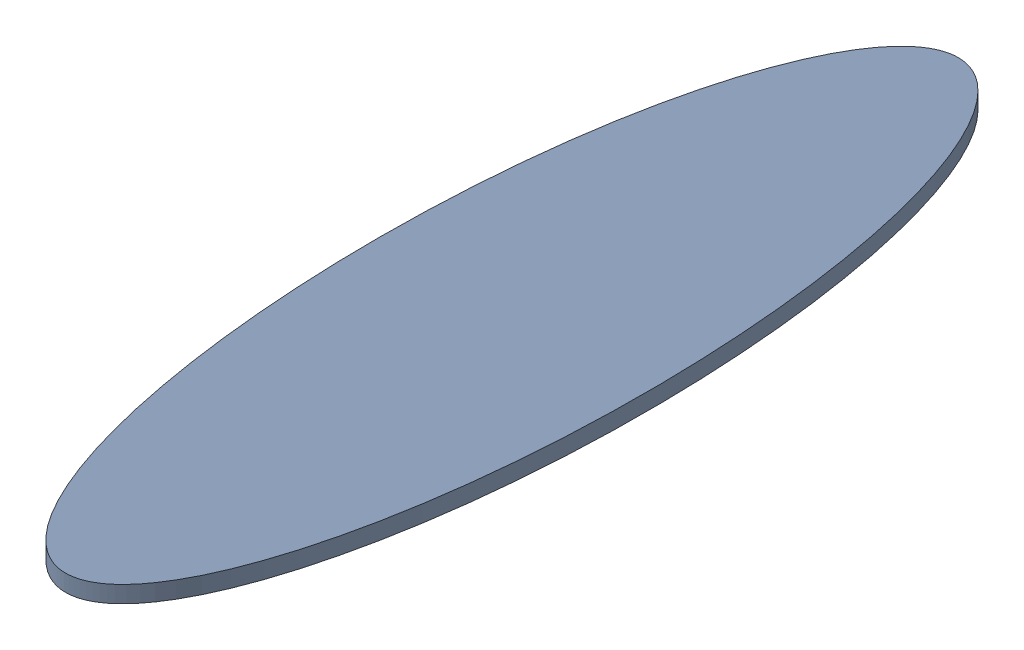
SolidWorks assembly Hopper, configuration Default. Lengths in mm.
Overall size (165.33 52.91 311.67).
16 component instances, 7 part files, 0 mates.
Components (placement in the parent):
- Top of body-1: Top of body [Default] at (-127.2337 -6.6665 -12.7668) size (76.2 4.76 254)
- body sides-1: body sides [Default] at (-113.8407 -19.3665 95.3384) (suppressed, hidden)
- body sides-2: body sides [Default] at (-148.2721 -18.2856 -106.385) (suppressed, hidden)
- body sides-3: body sides [Default] at (-145.6156 -19.3665 95.3738) (suppressed, hidden)
- body sides-4: body sides [Default] at (-111.1143 -18.4079 -106.64) (suppressed, hidden)
- upper leg-2: upper leg [Default] at (-150.3781 -35.4962 51.7951) x (1 0 0) z (0 -0.866025 0.5) (suppressed, hidden)
- upper leg-3: upper leg [Default] at (-110.0494 -34.158 51.4751) x (1 0 0) z (0 -0.882948 0.469472) (suppressed, hidden)
- front legs-2: front legs [Default] at (-144.3316 -71.4315 74.3988) x (1 0 0) z (0 0.944759 0.327765) (suppressed, hidden)
- front legs-3: front legs [Default] at (-99.2924 -76.5047 81.5262) x (1 0 0) z (0 0.945519 0.325568) (suppressed, hidden)
- upper leg-4: upper leg [Default] at (-103.7234 12.0089 -150.864) x (1 0 0) z (0 -0.794178 -0.607686) (suppressed, hidden)
- Lower back leg-2: Lower back leg [Default] at (-92.4111 -29.1812 -192.0599) x (1 0 0) z (0 0.97437 0.224951) (suppressed, hidden)
- compression-spring-1: compression-spring [1986K86] at (-106.7118 -3.3254 -121.5183) x (1 0 0) z (0 0.267238 0.96363) (suppressed, hidden)
- upper leg-5: upper leg [Default] at (-149.9556 16.9886 -143.8095) x (1 0 0) z (0 0.744051 0.668123) (suppressed, hidden)
- Lower back leg-3: Lower back leg [Default] at (-170.9643 -20.6483 -193.4561) x (1 0 0) z (0 0.945519 0.325568) (suppressed, hidden)
- compression-spring-2: compression-spring [1986K86] at (-155.6454 21.9494 -130.5867) x (1 0 0) z (0 0.34202 0.939693) (suppressed, hidden)
- trigger-1: trigger [Default] at (-133.6644 -66.0898 -273.1457) x (-1 0 0) z (0 0 -1) (suppressed, hidden)
